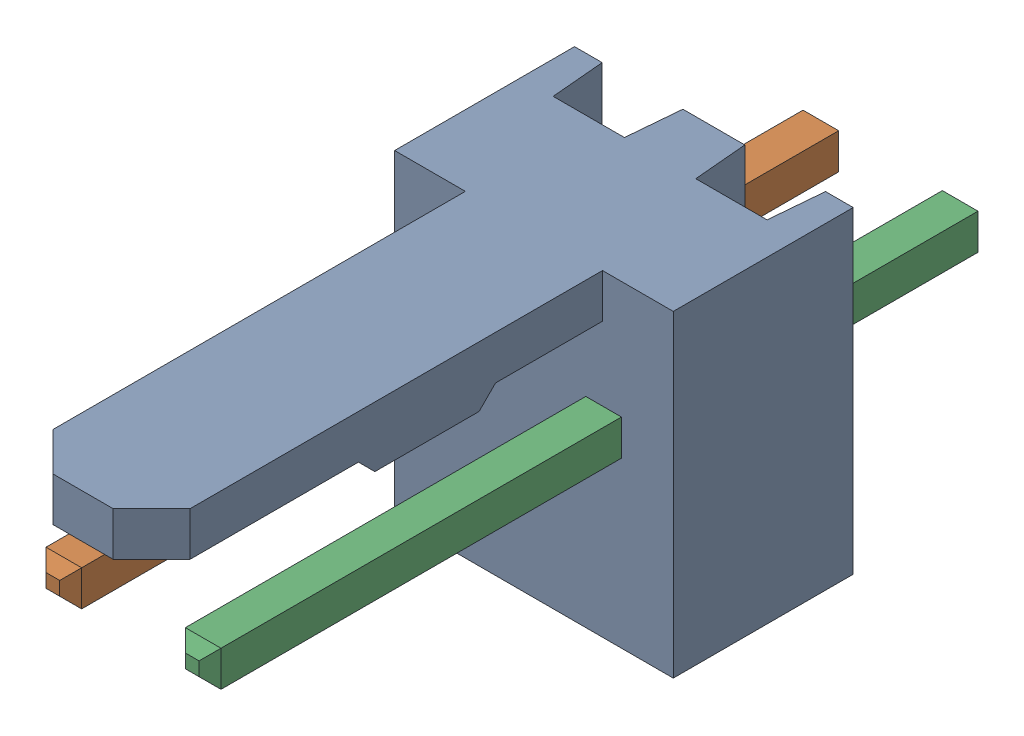
SolidWorks assembly Molex PCB 2 pin v2 (1), configuration Default. Lengths in mm.
Overall size (5.08 5.79 14.92).
3 component instances, 2 part files, 0 mates.
Components (placement in the parent):
- BASE9710016-1: BASE9710016 [Default] at (2.54 2.895 -8.22) size (5.08 5.79 11.5)
- PINO9710016-1: PINO9710016 [Default] at (1.27 3.325 -0.72) size (0.65 0.65 14.2)
- PINO9710016-2: PINO9710016 [Default] at (3.81 3.325 -0.72) size (0.65 0.65 14.2)
